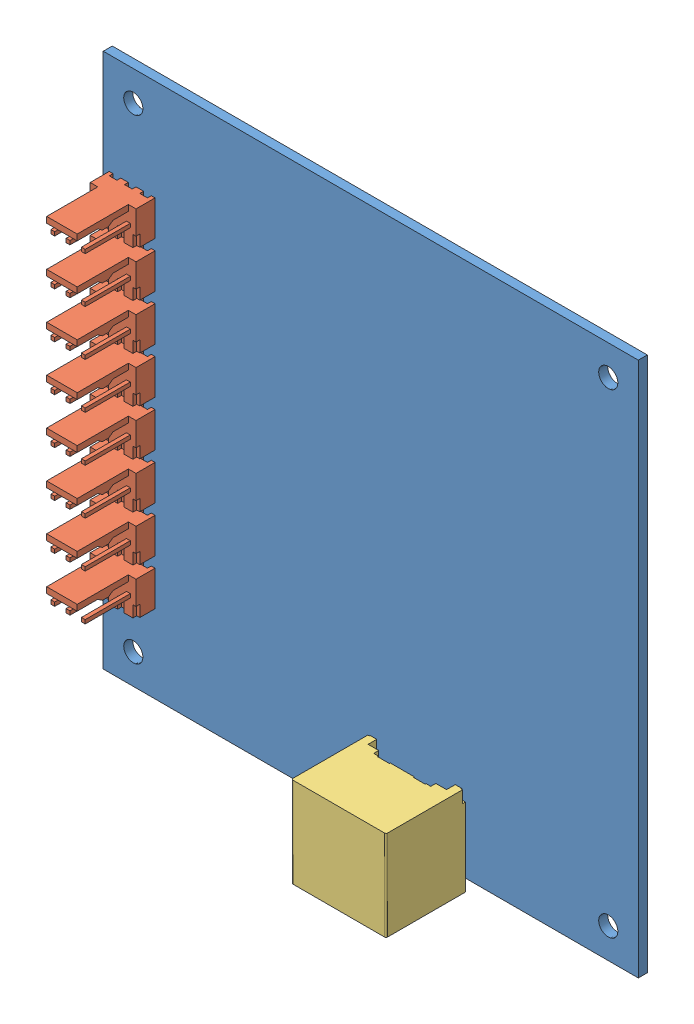
SolidWorks assembly MecaMainBoardAssembly, configuration Default. Lengths in mm.
Overall size (114.74 89 45.1).
10 component instances, 3 part files, 6 mates.
Components (placement in the parent):
- MecaMainBoard-1: MecaMainBoard [Default] at (-62.3061 11.3452 24.4203) size (89 89 1.5)
- User Library-molex kk 0_1in latching 3 way vertical header-1: User Library-molex kk 0_1in latching 3 way vertical header [Default] at (-101.9961 -17.183 27.5078) x (1 0 0) z (0 -1 0) size (7.62 15.24 5.84)
- User Library-molex kk 0_1in latching 3 way vertical header-2: User Library-molex kk 0_1in latching 3 way vertical header [Default] at (-101.9961 -9.563 27.5078) x (1 0 0) z (0 -1 0) size (7.62 15.24 5.84)
- User Library-molex kk 0_1in latching 3 way vertical header-3: User Library-molex kk 0_1in latching 3 way vertical header [Default] at (-101.9961 -1.943 27.5078) x (1 0 0) z (0 -1 0) size (7.62 15.24 5.84)
- User Library-molex kk 0_1in latching 3 way vertical header-4: User Library-molex kk 0_1in latching 3 way vertical header [Default] at (-101.9961 5.677 27.5078) x (1 0 0) z (0 -1 0) size (7.62 15.24 5.84)
- User Library-molex kk 0_1in latching 3 way vertical header-5: User Library-molex kk 0_1in latching 3 way vertical header [Default] at (-101.9961 13.297 27.5078) x (1 0 0) z (0 -1 0) size (7.62 15.24 5.84)
- User Library-molex kk 0_1in latching 3 way vertical header-6: User Library-molex kk 0_1in latching 3 way vertical header [Default] at (-101.9961 20.917 27.5078) x (1 0 0) z (0 -1 0) size (7.62 15.24 5.84)
- User Library-molex kk 0_1in latching 3 way vertical header-7: User Library-molex kk 0_1in latching 3 way vertical header [Default] at (-101.9961 28.537 27.5078) x (1 0 0) z (0 -1 0) size (7.62 15.24 5.84)
- User Library-molex kk 0_1in latching 3 way vertical header-8: User Library-molex kk 0_1in latching 3 way vertical header [Default] at (-101.9961 36.157 27.5078) x (1 0 0) z (0 -1 0) size (7.62 15.24 5.84)
- User Library-RJ11-6PM-1: User Library-RJ11-6PM [Default] at (-54.4321 -27.6618 32.5243) x (1 0 0) z (0 -1 0) size (15.88 16.36 14.99)
Mates (geometry in assembly coordinates):
- Coïncidente1: coincident anti-aligned: plane of MecaMainBoard-1 through (-62.3061 11.3452 25.9203) normal (0 0 1); plane of User Library-molex kk 0_1in latching 3 way vertical header-1 through (-105.9585 -20.2716 25.9203) normal (0 0 -1)
- Distance1: distance = 1 mm aligned: plane of User Library-molex kk 0_1in latching 3 way vertical header-1 through (-105.8061 -20.2716 25.8568) normal (-1 0 0); plane of MecaMainBoard-1 through (-106.8061 55.8452 25.9203) normal (-1 0 0)
- Distance2: distance = 13 mm aligned: plane of User Library-molex kk 0_1in latching 3 way vertical header-1 through (-105.9585 -20.1548 29.1588) normal (0 -1 0); plane of MecaMainBoard-1 through (-106.8061 -33.1548 25.9203) normal (0 -1 0)
- Coïncidente4: coincident: plane of MecaMainBoard-1 through (-62.3061 11.3452 25.9203) normal (0 0 1); plane of User Library-RJ11-6PM-1 through (-43.2997 -20.1688 25.9203) normal (0 0 -1)
- Distance3: distance = 2 mm: plane of User Library-RJ11-6PM-1 through (-54.4321 -35.1548 32.5243) normal (0 -1 0); plane of MecaMainBoard-1 through (-106.8061 -33.1548 25.9203) normal (0 -1 0)
- Distance4: distance = 44.5 mm aligned: plane of User Library-RJ11-6PM-1 through (-62.3061 -20.1688 39.1283) normal (-1 0 0); plane of MecaMainBoard-1 through (-106.8061 55.8452 25.9203) normal (-1 0 0)
